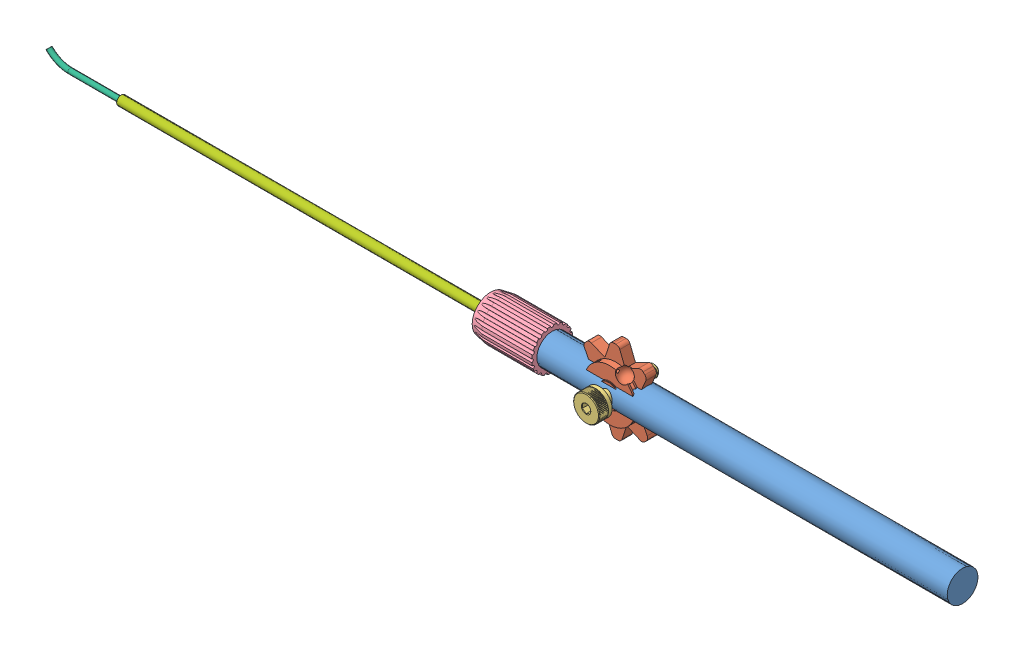
SolidWorks assembly assem_handle_ent, configuration Default. Lengths in mm.
Overall size (223.04 20.59 17.04).
7 component instances, 7 part files, 12 mates.
Components (placement in the parent):
- wheel_handle_body v-2 17-Jan-2017-1: wheel_handle_body v-2 17-Jan-2017 [Default] at (-1.7001 72.104 100.1495) size (100 7.5 13.5)
- wheel_ent-1: wheel_ent [Default] at (15.0499 72.104 101.3995) x (0.999556 0.02978 0) z (0 0 1) size (20 20 4.62)
- 91259A156_ALLOY STEEL SHOULDER SCREW-1: 91259A156_ALLOY STEEL SHOULDER SCREW [91259A156] at (15.0499 72.104 105.4671) x (0.995863 -0.090867 0) z (-0.090867 -0.995863 0) size (6.35 17.04 6.35)
- V06_Collet_ThreadCap-1: V06_Collet_ThreadCap [Default] at (-16.7001 72.104 100.1495) x (0 -1 0) z (0 0 1) size (10.31 15 10.31)
- Collet_1_75mmID-1: Collet_1_75mmID [Default] at (2.0499 72.104 100.1495) x (0 0.206262 0.978497) z (-1 0 0) size (5.98 5.98 18.75)
- nitinol notched tube v-1 17-Jan-2017-1: nitinol notched tube v-1 17-Jan-2017 [Default] at (-50.7459 72.104 100.1495) size (18.04 3.26 1.22)
- stainless steel rod v-1 17-Jan-2017-1: stainless steel rod v-1 17-Jan-2017 [Default] at (-106.7001 72.104 100.1495) size (90 2.25 2.25)
Mates (geometry in assembly coordinates):
- Coincident1: coincident anti-aligned: circle of wheel_handle_body v-2 17-Jan-2017-1; plane of wheel_ent-1 through (15.0499 72.104 103.1495) normal (0 0 1)
- Concentric1: concentric anti-aligned: circle of wheel_handle_body v-2 17-Jan-2017-1; circle of 91259A156_ALLOY STEEL SHOULDER SCREW-1
- Concentric2: concentric anti-aligned: circle of wheel_ent-1; cylinder of 91259A156_ALLOY STEEL SHOULDER SCREW-1 through (15.0499 72.104 105.4671) axis (0 0 -1) radius 1.5875
- Coincident2: coincident anti-aligned: plane of wheel_handle_body v-2 17-Jan-2017-1 through (-1.7001 72.104 100.1495) normal (-1 0 0); plane of V06_Collet_ThreadCap-1 through (-1.7001 72.104 100.1495) normal (1 0 0)
- Concentric3: concentric aligned: circle of wheel_handle_body v-2 17-Jan-2017-1; circle of V06_Collet_ThreadCap-1
- Coincident3: coincident aligned: plane of V06_Collet_ThreadCap-1 through (-16.7001 72.104 100.1495) normal (-1 0 0); plane of Collet_1_75mmID-1 through (-16.7001 72.104 100.1495) normal (-1 0 0)
- Concentric5: concentric aligned: circle of V06_Collet_ThreadCap-1; circle of Collet_1_75mmID-1
- Coincident4: coincident anti-aligned: plane of Collet_1_75mmID-1 through (-16.7001 72.104 100.1495) normal (-1 0 0); plane of stainless steel rod v-1 17-Jan-2017-1 through (-16.7001 72.104 100.1495) normal (1 0 0)
- Concentric6: concentric anti-aligned: circle of V06_Collet_ThreadCap-1; circle of stainless steel rod v-1 17-Jan-2017-1
- Coincident5: coincident: plane of nitinol notched tube v-1 17-Jan-2017-1 through (-106.7001 72.104 100.1495) normal (1 0 0); plane of stainless steel rod v-1 17-Jan-2017-1 through (-106.7001 72.104 100.1495) normal (-1 0 0)
- Concentric7: concentric: circle of nitinol notched tube v-1 17-Jan-2017-1; circle of stainless steel rod v-1 17-Jan-2017-1
- Coincident6: coincident anti-aligned: plane of nitinol notched tube v-1 17-Jan-2017-1 through (-106.7001 72.104 100.1495) normal (1 0 0); plane of stainless steel rod v-1 17-Jan-2017-1 through (-106.7001 72.104 100.1495) normal (-1 0 0)
